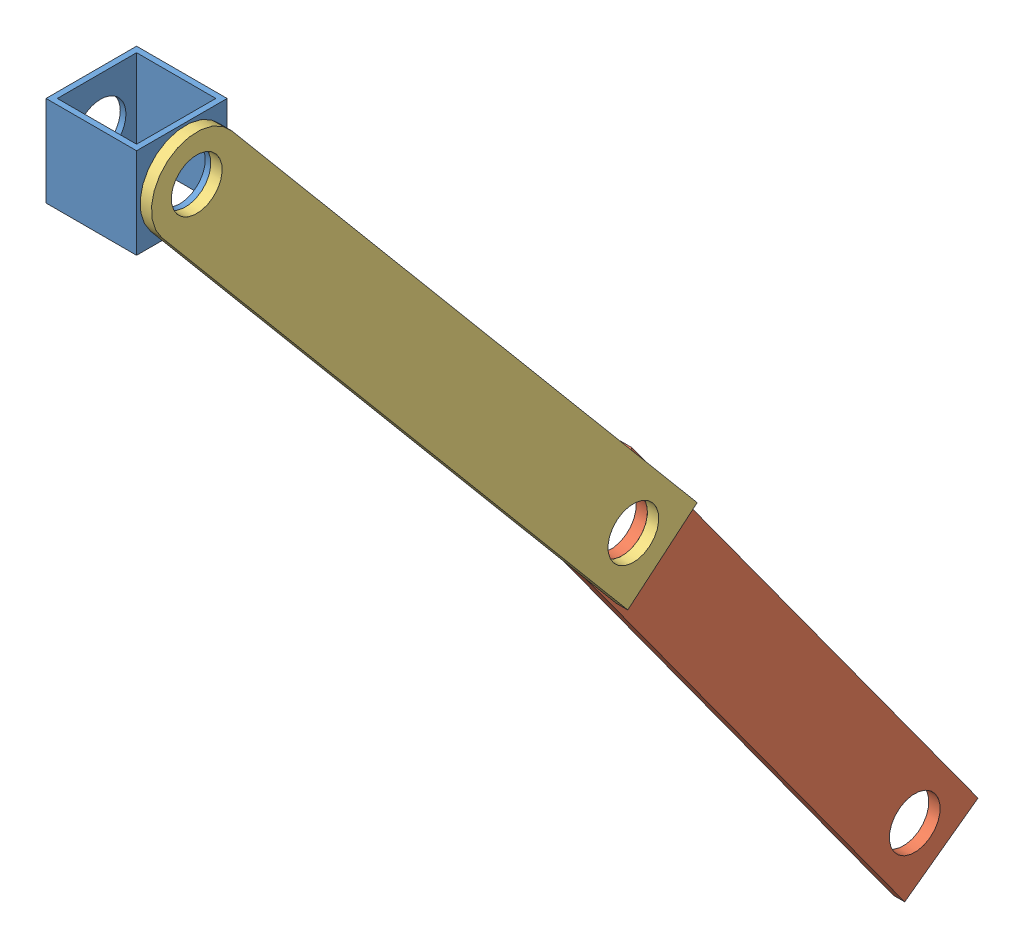
SolidWorks assembly Arm, configuration Default. Lengths in mm.
Overall size (57.15 589.22 480.31).
3 component instances, 3 part files, 2 mates.
Components (placement in the parent):
- Tubing for arm-1: Tubing for arm [Default] at (31.4948 10.5256 43.2398) size (50.8 50.8 50.8)
- Bar For Arm 2-2: Bar For Arm 2 [Default] at (50.5448 -518.8979 -362.1613) x (0 0.58754 -0.809195) z (0 -0.809195 -0.58754) size (50.8 6.35 330.2)
- Arm Bar Rounded end-1: Arm Bar Rounded end [Default] at (63.2448 18.2169 60.7139) x (0 0.642751 -0.766075) z (0 0.766075 0.642751) size (50.8 6.35 431.8)
Mates (geometry in assembly coordinates):
- Coincident12: coincident: circle of Tubing for arm-1; circle of Arm Bar Rounded end-1
- Coincident14: coincident: circle of Bar For Arm 2-2; circle of Arm Bar Rounded end-1
